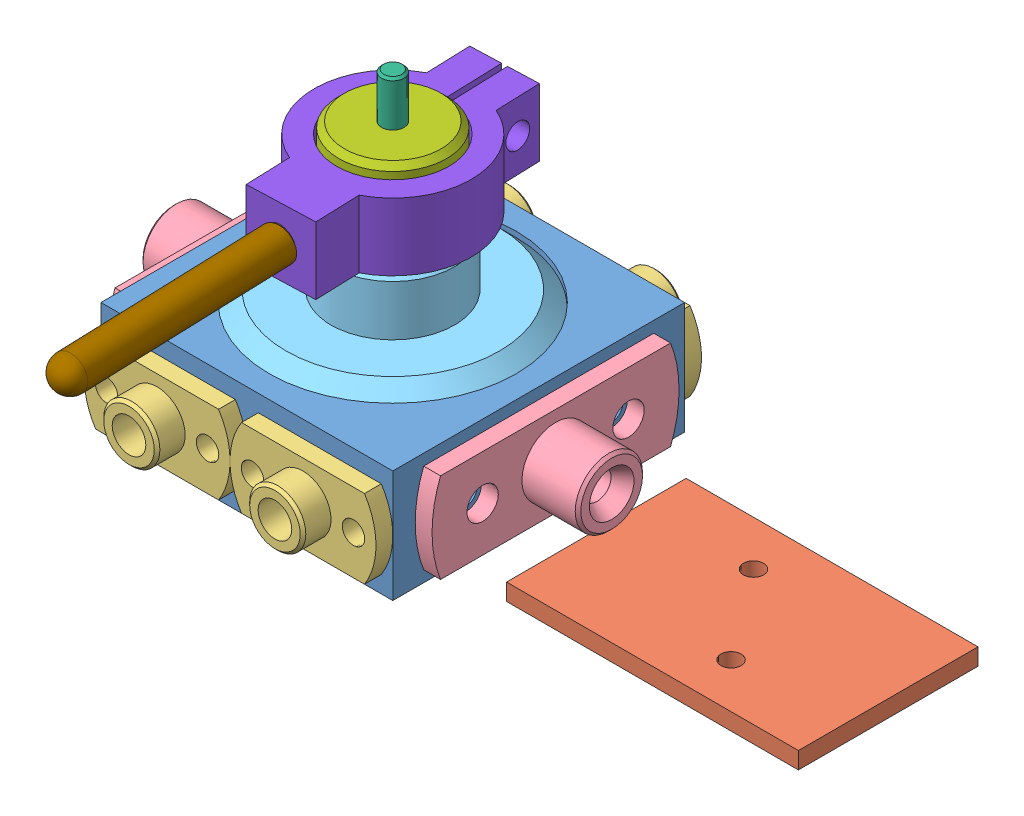
SolidWorks assembly Shifter Assembly, configuration Default. Lengths in mm.
Overall size (63.64 28 48.36).
13 component instances, 9 part files, 31 mates.
Components (placement in the parent):
- Part 25-1: Part 25 [Default] at (11.3293 9.117 18.7273) size (26 10 26)
- Part 25a-1: Part 25a [Default] at (42.465 9.117 18.7273) size (26 1.5 16)
- Part 29-1: Part 29 [Default] at (17.8293 14.117 31.7273) x (1 0 0) z (0 -1 0) size (13 4 7)
- Part 30-1: Part 30 [Default] at (24.3293 14.117 18.7273) x (0 0 -1) z (0 -1 0) size (22 6.5 8)
- Part 26-1: Part 26 [Default] at (11.3293 16.117 18.7273) size (22 10 22)
- Part 26a-1: Part 26a [Default] at (11.3293 16.117 18.7273) x (-0.468722 0 0.883346) z (0 -1 0) size (5 5 24)
- part 26b-1: part 26b [Default] at (11.3293 33.117 18.7273) x (0.580162 0 0.814501) z (0 -1 0) size (9.6 9.6 7)
- Part 30-2: Part 30 [Default] at (-1.6707 14.117 18.7273) x (0 0 1) z (0 -1 0) size (22 6.5 8)
- Part 29-2: Part 29 [Default] at (17.8293 14.117 5.7273) x (-1 0 0) z (0 -1 0) size (13 4 7)
- Part 29-3: Part 29 [Default] at (4.8293 14.117 5.7273) x (-1 0 0) z (0 -1 0) size (13 4 7)
- Part 29-4: Part 29 [Default] at (4.8293 14.117 31.7273) x (1 0 0) z (0 -1 0) size (13 4 7)
- Part 27-1: Part 27 [Default] at (11.3293 26.117 18.7273) x (0.999395 0 -0.034773) z (0.034773 0 0.999395) size (14 6.09 20.65)
- Part 27a-1: Part 27a [Default] at (11.5492 29.117 25.048) x (0.999395 0 -0.034773) z (0 -1 0) size (3.06 25 3.52)
Mates (geometry in assembly coordinates):
- Coincident1: coincident anti-aligned: plane of Part 25-1 through (24.3293 19.117 31.7273) normal (1 0 0); plane of Part 30-1 through (24.3293 14.117 18.7273) normal (-1 0 0)
- Concentric1: concentric aligned: cylinder of Part 25-1 through (24.3293 14.117 18.7273) axis (1 0 0) radius 1; cylinder of Part 30-1 through (30.8293 14.117 18.7273) axis (1 0 0) radius 1.25
- Concentric2: concentric aligned: circle of Part 25-1; circle of Part 30-1
- Coincident2: coincident anti-aligned: plane of Part 25-1 through (-1.6707 19.117 31.7273) normal (0 0 1); plane of Part 29-1 through (17.8293 14.117 31.7273) normal (0 0 -1)
- Concentric3: concentric aligned: circle of Part 25-1; circle of Part 29-1
- Concentric4: concentric aligned: cylinder of Part 25-1 through (22.3293 14.117 31.7273) axis (0 0 1) radius 0.65; circle of Part 29-1
- Concentric5: concentric aligned: cylinder of Part 25-1 through (13.3293 14.117 31.7273) axis (0 0 1) radius 0.65; circle of Part 29-1
- Coincident3: coincident anti-aligned: plane of Part 25-1 through (-1.6707 10.617 26.7273) normal (0 0 -1); plane of Part 25a-1 through (29.465 10.617 26.7273) normal (0 0 1)
- Concentric6: concentric aligned: circle of Part 25-1; cylinder of Part 26-1 through (11.3293 20.117 18.7273) axis (0 -1 0) radius 11
- Concentric7: concentric anti-aligned: circle of Part 25-1; circle of Part 26a-1
- Concentric8: concentric anti-aligned: circle of Part 26a-1; circle of part 26b-1
- Coincident5: coincident anti-aligned: plane of Part 25-1 through (11.3293 16.117 18.7273) normal (0 1 0); plane of Part 26a-1 through (11.3293 16.117 18.7273) normal (0 -1 0)
- Coincident7: coincident anti-aligned: plane of Part 26-1 through (11.3293 26.117 18.7273) normal (0 1 0); plane of part 26b-1 through (11.3293 26.117 18.7273) normal (0 -1 0)
- Coincident8: coincident anti-aligned: plane of Part 25-1 through (11.3293 16.117 18.7273) normal (0 1 0); plane of Part 26-1 through (11.3293 16.117 18.7273) normal (0 -1 0)
- Coincident9: coincident anti-aligned: plane of Part 25-1 through (-1.6707 19.117 31.7273) normal (-1 0 0); plane of Part 30-2 through (-1.6707 14.117 18.7273) normal (1 0 0)
- Concentric9: concentric aligned: circle of Part 25-1; cylinder of Part 30-2 through (-3.1707 14.117 25.2273) axis (-1 0 0) radius 1.4
- Concentric10: concentric aligned: circle of Part 25-1; circle of Part 30-2
- Coincident10: coincident anti-aligned: plane of Part 25-1 through (-1.6707 19.117 31.7273) normal (0 0 1); plane of Part 29-4 through (4.8293 14.117 31.7273) normal (0 0 -1)
- Concentric11: concentric anti-aligned: circle of Part 25-1; cylinder of Part 29-4 through (9.3293 14.117 31.7273) axis (0 0 -1) radius 1
- Concentric12: concentric anti-aligned: cylinder of Part 25-1 through (0.3293 14.117 31.7273) axis (0 0 1) radius 0.65; cylinder of Part 29-4 through (0.3293 14.117 31.7273) axis (0 0 -1) radius 1
- Coincident11: coincident anti-aligned: plane of Part 25-1 through (-1.6707 19.117 5.7273) normal (0 0 -1); plane of Part 29-3 through (4.8293 14.117 5.7273) normal (0 0 1)
- Concentric13: concentric anti-aligned: circle of Part 25-1; cylinder of Part 29-3 through (9.3293 14.117 5.7273) axis (0 0 1) radius 1
- Concentric14: concentric aligned: circle of Part 25-1; circle of Part 29-3
- Coincident12: coincident anti-aligned: plane of Part 25-1 through (-1.6707 19.117 5.7273) normal (0 0 -1); plane of Part 29-2 through (17.8293 14.117 5.7273) normal (0 0 1)
- Concentric15: concentric aligned: circle of Part 25-1; circle of Part 29-2
- Concentric16: concentric aligned: circle of Part 25-1; circle of Part 29-2
- Concentric17: concentric anti-aligned: cylinder of Part 27-1 through (11.6883 29.117 29.0456) axis (0.034773 0 0.999395) radius 1.25; cylinder of Part 27a-1 through (11.5492 29.117 25.048) axis (-0.034773 0 -0.999395) radius 1.525
- Coincident13: coincident anti-aligned: circle of Part 27-1; plane of Part 27a-1 through (11.5492 29.117 25.048) normal (-0.034773 0 -0.999395)
- Concentric18: concentric aligned: circle of part 26b-1; cylinder of Part 27-1 through (11.3293 32.117 18.7273) axis (0 -1 0) radius 5
- Coincident14: coincident aligned: plane of part 26b-1 through (11.3293 26.117 18.7273) normal (0 -1 0); plane of Part 27-1 through (11.3293 26.117 18.7273) normal (0 -1 0)
- Coincident17: coincident anti-aligned: plane of Part 25-1 through (11.3293 10.617 18.7273) normal (0 -1 0); plane of Part 25a-1 through (42.465 10.617 18.7273) normal (0 1 0)
